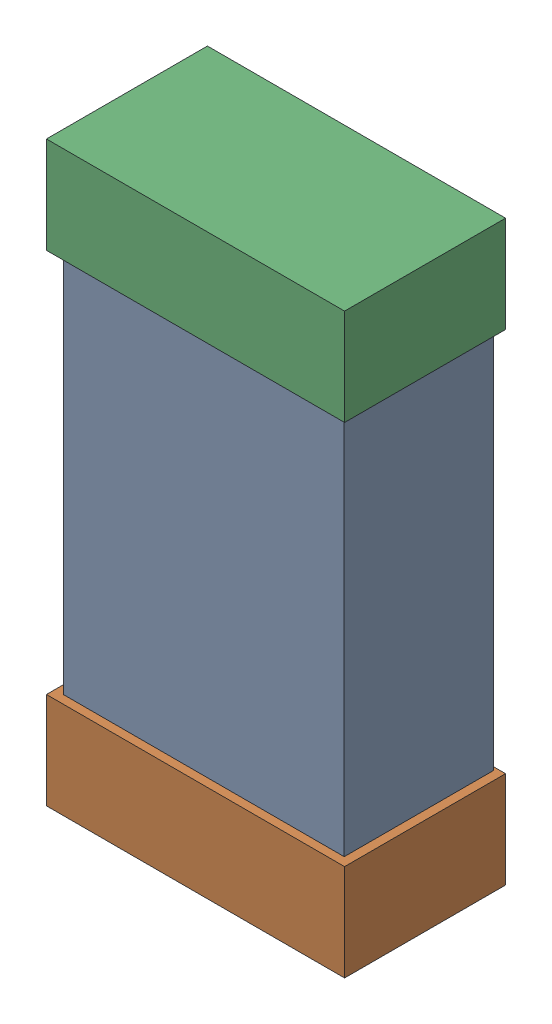
SolidWorks assembly R20, configuration Default. Lengths in mm.
Overall size (0.85 1.65 0.46).
6 component instances, 2 part files, 0 mates.
Components (placement in the parent):
- 432124816_52-1: 432124816_52 [Default] at (29.175 4.4434 -0.8615) size (0.8 1.5 0.42)
  - Extruded (1)-1: Extruded (1) [Default] at origin size (0.8 1.5 0.42)
- 432138512_104-1: 432138512_104 [Default] at (29.175 3.7576 -0.8715) size (0.85 0.28 0.46)
  - Extruded-1: Extruded [Default] at origin size (0.85 0.28 0.46)
- 432138512_105-1: 432138512_105 [Default] at (29.175 5.1291 -0.8715) size (0.85 0.28 0.46)
  - Extruded-1: Extruded [Default] at origin size (0.85 0.28 0.46)
